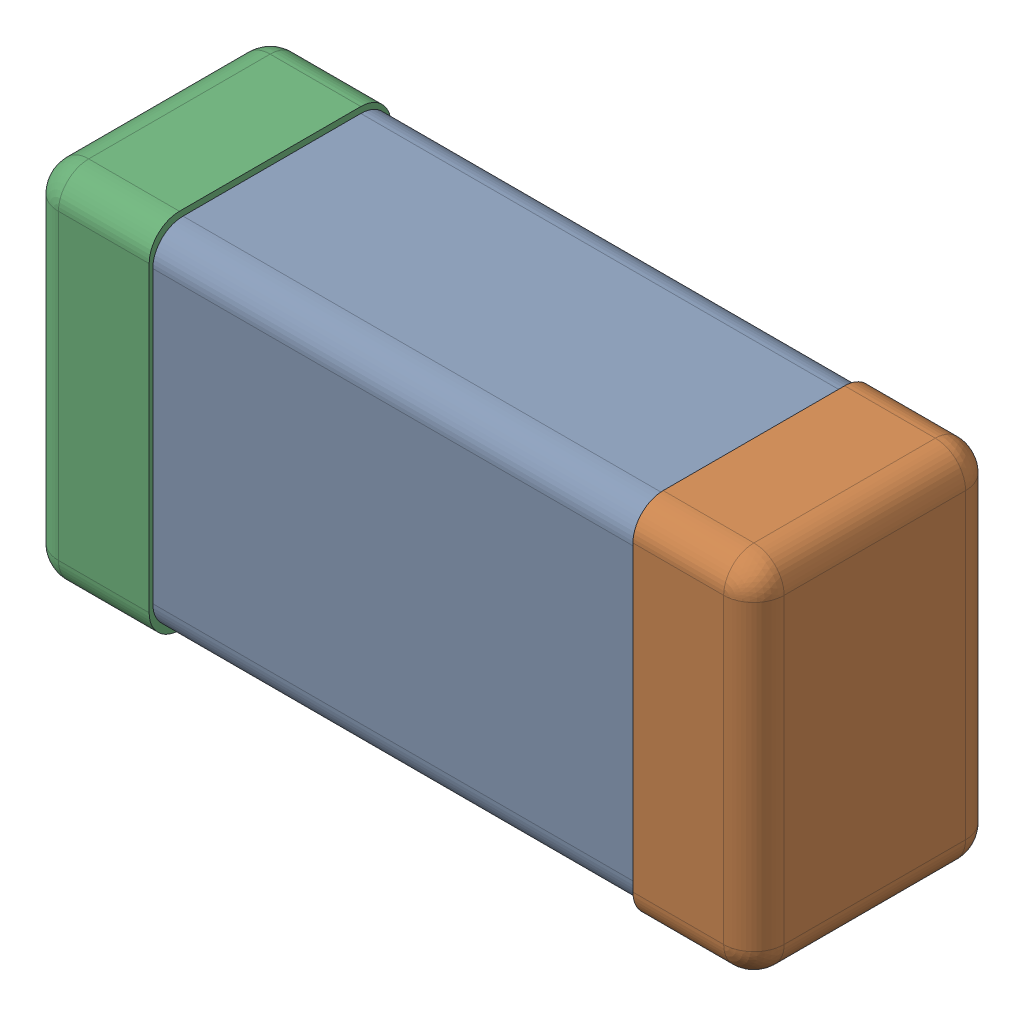
SolidWorks assembly C0201_020_35, configuration Standard. Lengths in mm.
Overall size (0.6 0.3 0.2).
3 component instances, 3 part files, 0 mates.
Components (placement in the parent):
- Part 3_2-1: Part 3_2 [Standard] at (0 0 -7.3015) size (0.5 0.29 0.2)
- Part 2_2-1: Part 2_2 [Standard] at (0 0 -7.3) size (0.1 0.3 0.2)
- Part 1_2-1: Part 1_2 [Standard] at (0 0 -7.3) size (0.1 0.3 0.2)
